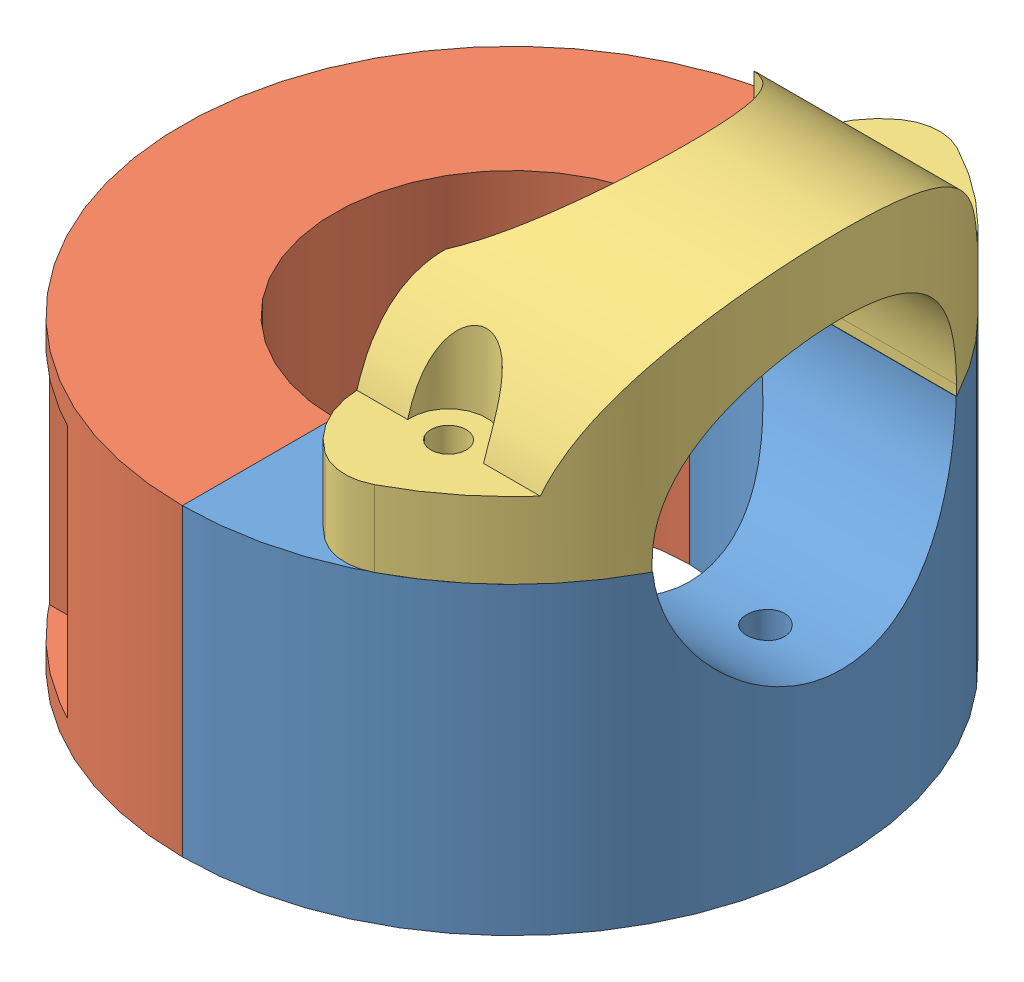
SolidWorks assembly SOLAR_COLLAR, configuration Default. Lengths in mm.
Overall size (165.1 135.89 165.1).
3 component instances, 3 part files, 4 mates.
Components (placement in the parent):
- C_COLLAR_IN-1: C_COLLAR_IN [Default] at (19.0525 35.5175 135.07) size (82.55 78.74 165.1)
- C_COLLAR_OUT-1: C_COLLAR_OUT [Default] at (19.0525 35.5175 135.07) x (-1 0 0) z (0 0 -1) size (82.55 76.2 165.1)
- C_COLLAR_CUPCAP-1: C_COLLAR_CUPCAP [Default] at (19.0525 111.7175 135.07) size (66.67 59.98 148.93)
Mates (geometry in assembly coordinates):
- Coincident1: coincident: circle of C_COLLAR_IN-1; circle of C_COLLAR_OUT-1
- Coincident2: coincident anti-aligned: circle of C_COLLAR_IN-1; circle of C_COLLAR_OUT-1
- Concentric1: concentric: cylinder of C_COLLAR_IN-1 through (19.0525 111.7175 135.07) axis (0 -1 0) radius 44.45; cylinder of C_COLLAR_CUPCAP-1 through (19.0525 187.9175 135.07) axis (0 -1 0) radius 44.45
- Coincident3: coincident aligned: circle of C_COLLAR_IN-1; circle of C_COLLAR_CUPCAP-1
